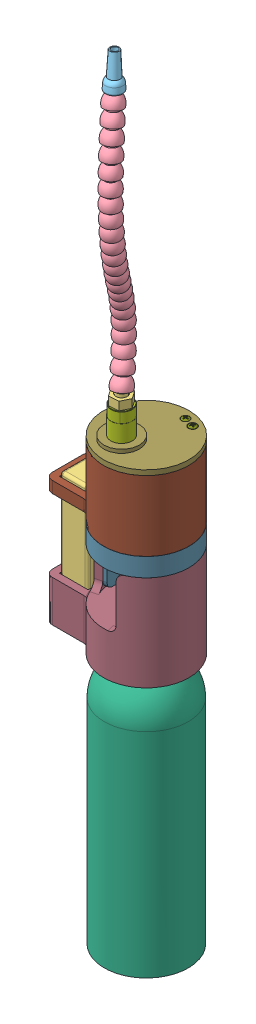
SolidWorks assembly _Robocup_Assembly_Wide_Straw_Thermos_, configuration Default. Lengths in mm.
Overall size (108.56 713.03 103.97).
85 component instances, 35 part files, 77 mates.
Components (placement in the parent):
- SF3218MG Servo-1: SF3218MG Servo [Default] at (-17.653 -62.7888 -19.9) size (54.86 45.72 19.05)
- Servo gear 30t-1: Servo gear 30t [Default] at (-7.993 -20.4688 -10.375) x (-0.381225 0 -0.924482) z (0 1 0) size (25.51 25.6 6)
- Coolant Pipe.stp-1: Coolant Pipe.stp [Default] at (-8.06 46.6882 14.01) x (0.568385 0 0.822762) z (-0.822762 0 0.568385) size (74.23 300.91 26.18)
  - Coolant Bolt.stp-1: Coolant Bolt.stp [Default] x (-1 0 0) z (0 0 1) size (17.61 27.5 15.25)
  - Connectors.stp-1: Connectors.stp [Default] at (-2.2835 3.6671 -0.0362) x (-0.321951 -0.100327 -0.941426) z (0.285439 -0.958386 0.00452) size (18.3 18.3 20)
  - Connectors.stp-2: Connectors.stp [Default] at (-0.9485 62.1668 -0.2193) x (0.834188 -0.338799 0.435138) z (-0.378337 -0.925657 0.00458) size (18.3 18.3 20)
  - Connectors.stp-3: Connectors.stp [Default] at (-7.0218 39.1054 -0.1142) x (0.974617 -0.052931 0.217534) z (-0.054998 -0.99848 0.003454) size (18.3 18.3 20)
  - Connectors.stp-4: Connectors.stp [Default] at (-7.018 27.1423 -0.0887) x (-0.288884 -0.031731 -0.956838) z (0.11095 -0.993826 -0.00054) size (18.3 18.3 20)
  - Connectors.stp-5: Connectors.stp [Default] at (10.0914 83.4503 -0.3173) x (0.525964 -0.304704 -0.794051) z (-0.497138 -0.867664 0.003658) size (18.3 18.3 20)
  - Connectors.stp-6: Connectors.stp [Default] at (4.2645 72.9625 -0.2712) x (0.886562 -0.462353 0.015441) z (-0.462461 -0.88663 0.004202) size (18.3 18.3 20)
  - Connectors.stp-7: Connectors.stp [Default] at (-4.9174 50.8742 -0.1644) x (0.803108 -0.192004 0.56405) z (-0.235547 -0.971852 0.004557) size (18.3 18.3 20)
  - Connectors.stp-8: Connectors.stp [Default] at (16.0513 93.8656 -0.3564) x (0.86534 -0.495122 -0.077724) z (-0.496415 -0.86808 0.003062) size (18.3 18.3 20)
  - Connectors.stp-9: Connectors.stp [Default] at (35.5838 137.5772 -0.4345) x (0.770438 -0.236558 0.592002) z (-0.293738 -0.955886 0.000312) size (18.3 18.3 20)
  - Connectors.stp-10: Connectors.stp [Default] at (38.4122 149.228 -0.4322) x (0.672162 -0.141658 -0.726727) z (-0.20668 -0.978409 -0.000445) size (18.3 18.3 20)
  - Connectors.stp-11: Connectors.stp [Default] at (31.7619 126.2108 -0.4277) x (0.912958 -0.361121 0.189996) z (-0.368012 -0.929821 0.001063) size (18.3 18.3 20)
  - Connectors.stp-12: Connectors.stp [Default] at (21.8052 104.3949 -0.3882) x (-0.461711 0.244191 -0.852756) z (-0.471034 -0.882112 0.002437) size (18.3 18.3 20)
  - Connectors.stp-13: Connectors.stp [Default] at (-5.2287 15.2947 -0.0801) x (0.757626 0.173214 -0.629285) z (0.225426 -0.974255 0.003232) size (18.3 18.3 20)
  - Connectors.stp-14: Connectors.stp [Default] at (27.1083 115.1559 -0.4121) x (0.901968 -0.4265 -0.067469) z (-0.427365 -0.904078 0.001774) size (18.3 18.3 20)
  - Coolant Pipe Nozzle.stp-1: Coolant Pipe Nozzle.stp [Default] at (27.898 246.6708 -0.2231) x (-0.153795 -0.02183 0.987862) z (0.098368 -0.995128 -0.006677) size (15 15 30)
  - Connectors.stp-15: Connectors.stp [Default] at (40.4307 185.0487 -0.3789) x (0.938856 0.053217 -0.340172) z (0.055817 -0.998439 -0.002147) size (18.3 18.3 20)
  - Connectors.stp-16: Connectors.stp [Default] at (39.2092 196.9799 -0.3507) x (0.937442 0.118696 -0.327281) z (0.124773 -0.992182 -0.002445) size (18.3 18.3 20)
  - Connectors.stp-17: Connectors.stp [Default] at (40.784 173.0623 -0.4029) x (0.972219 -0.02226 -0.233011) z (-0.023301 -0.999727 -0.001718) size (18.3 18.3 20)
  - Connectors.stp-18: Connectors.stp [Default] at (40.1447 161.0902 -0.4212) x (0.882181 -0.100002 -0.460169) z (-0.113225 -0.993569 -0.001143) size (18.3 18.3 20)
  - Connectors.stp-19: Connectors.stp [Default] at (31.9646 232.2183 -0.2574) x (0.793284 0.199128 0.575369) z (0.245233 -0.969461 -0.002594) size (18.3 18.3 20)
  - Connectors.stp-20: Connectors.stp [Default] at (37.2637 208.8167 -0.3201) x (0.26581 0.051415 -0.962653) z (0.180811 -0.983514 -0.002604) size (18.3 18.3 20)
  - Connectors.stp-21: Connectors.stp [Default] at (28.861 243.8093 -0.2266) x (0.725081 0.197806 0.659645) z (0.26534 -0.964151 -0.002545) size (18.3 18.3 20)
  - Connectors.stp-22: Connectors.stp [Default] at (34.7978 220.5587 -0.2886) x (0.975424 0.217793 -0.033387) z (0.217828 -0.975984 -0.002632) size (18.3 18.3 20)
- Thermos-1: Thermos [Default] at (0 -388.9327 0) x (0.026685 0 0.999644) z (-0.999644 0 0.026685) size (74.93 250.19 74.93)
- Arduino Nano.STEP-1: Arduino Nano.STEP [Default] at (17.196 -13.0397 29.7784) x (0 -1 0) z (1 0 0) size (44.28 18 13.68)
  - ATMEGA328P-AU.STEP.STEP-1: ATMEGA328P-AU.STEP.STEP [Default] at (19.8219 24.4243 4.0882) x (-0.707107 -0.707107 0) z (0 0 1) size (9 9 1.2)
    - ATMEGA328P-AU--3DModel-STEP-56544.step.STEP.STEP.STEP.STEP-1: ATMEGA328P-AU--3DModel-STEP-56544.step.STEP.STEP.STEP.STEP [Default] at (2.8163 4.1 0.6768) x (1 0 0) z (0 -1 0) size (9 1.2 9)
  - Arduino Nano.STEP-1: Arduino Nano.STEP [Default] at (8.8551 11.9484 0) size (43.18 18 6.8)
  - Mini USB.STEP-1: Mini USB.STEP [Default] at (8.5451 19.5727 4.14) size (9.5 9.7 3.9)
  - CSTCE Crystal.STEP-1: CSTCE Crystal.STEP [Default] at (25.8562 23.1047 4.15) x (0.707107 -0.707107 0) z (0 0 1) size (3.2 1.35 0.71)
  - 2Pin Tactile Switch 6x3.6.STEP-1: 2Pin Tactile Switch 6x3.6.STEP [Default] at (30.7142 19.8184 4.14) x (0 1 0) z (0 0 1) size (7.9 3.6 2.2)
  - 0603 Resistor.STEP-1: 0603 Resistor.STEP [Default] at (34.4251 22.4184 4.14) size (1.6 0.8 0.5)
  - 0603 Resistor.STEP-2: 0603 Resistor.STEP [Default] at (34.4251 20.7184 4.14) size (1.6 0.8 0.5)
  - 0603 Resistor.STEP-3: 0603 Resistor.STEP [Default] at (34.4251 18.9184 4.14) size (1.6 0.8 0.5)
  - 0603 Resistor.STEP-4: 0603 Resistor.STEP [Default] at (34.4251 17.2184 4.14) size (1.6 0.8 0.5)
  - Blue LED.STEP-1: Blue LED.STEP [Default] at (37.0251 22.4184 4.14) size (1.6 0.8 0.6)
  - Green LED.STEP-1: Green LED.STEP [Default] at (37.0251 20.7184 4.14) size (1.6 0.8 0.6)
  - Red LED.STEP-1: Red LED.STEP [Default] at (37.0251 18.9184 4.14) size (1.6 0.8 0.6)
  - Blue LED.STEP-2: Blue LED.STEP [Default] at (37.0251 17.2184 4.14) size (1.6 0.8 0.6)
  - Header 2x3.STEP-1: Header 2x3.STEP [Default] at (45.6765 17.0321 4.14) x (0 1 0) z (0 0 1) size (7.62 5.07 10)
  - SOT89.STEP-1: SOT89.STEP [Default] at (38.4751 17.3184 0.94) x (0 1 0) z (0 0 1) size (6.5 7.1 1.6)
  - 1206 Tantalum.STEP-1: 1206 Tantalum.STEP [Default] at (38.6251 22.3684 2.54) x (-1 0 0) z (0 0 -1) size (3.2 1.6 1.5)
  - 0603 Resistor.STEP-5: 0603 Resistor.STEP [Default] at (38.4251 24.9684 2.54) x (-1 0 0) z (0 0 -1) size (1.6 0.8 0.5)
  - 0603 Capacitor.STEP-1: 0603 Capacitor.STEP [Default] at (35.0338 14.4684 2.54) x (-1 0 0) z (0 0 -1) size (1.6 0.8 0.7)
  - 1206 Tantalum.STEP-2: 1206 Tantalum.STEP [Default] at (7.6451 24.3684 2.54) x (1 0 0) z (0 0 -1) size (3.2 1.6 1.5)
  - 0603 Capacitor.STEP-2: 0603 Capacitor.STEP [Default] at (6.9059 22.4745 2.54) x (-1 0 0) z (0 0 -1) size (1.6 0.8 0.7)
  - 0603 Capacitor.STEP-3: 0603 Capacitor.STEP [Default] at (17.8451 14.0245 2.54) x (-1 0 0) z (0 0 -1) size (1.6 0.8 0.7)
  - 0603 Capacitor.STEP-4: 0603 Capacitor.STEP [Default] at (17.8451 15.0767 2.54) x (-1 0 0) z (0 0 -1) size (1.6 0.8 0.7)
  - 0603 Capacitor.STEP-5: 0603 Capacitor.STEP [Default] at (25.3451 21.2855 2.54) x (-1 0 0) z (0 0 -1) size (1.6 0.8 0.7)
  - 0603 Resistor.STEP-6: 0603 Resistor.STEP [Default] at (23.8451 15.8601 2.54) x (-1 0 0) z (0 0 -1) size (1.6 0.8 0.5)
  - 0603 Resistor.STEP-7: 0603 Resistor.STEP [Default] at (23.8451 14.4709 2.54) x (-1 0 0) z (0 0 -1) size (1.6 0.8 0.5)
  - CSTCE Crystal.STEP-2: CSTCE Crystal.STEP [Default] at (13.1731 14.7184 2.53) x (-1 0 0) z (0 0 -1) size (3.2 1.35 0.71)
  - SOIC16.STEP-1: SOIC16.STEP [Default] at (16.6451 19.5642 2.54) x (-1 0 0) z (0 0 -1) size (10.2 6 1.5)
- 5V Battery-1: 5V Battery [Default] at (-51.308 -151.4427 0) x (-1 0 0) z (0 0 -1) size (24.89 102.87 26.92)
- 5111K751_Push-to-Connect Tube Fitting for Air and Water-1: 5111K751_Push-to-Connect Tube Fitting for Air and Water [5111K751] at (-3.81 -156.8527 6.5991) x (-0.837169 0 -0.546944) z (-0.546944 0 0.837169) size (20.16 24.38 17.46)
- 5111K751_Push-to-Connect Tube Fitting for Air and Water-2: 5111K751_Push-to-Connect Tube Fitting for Air and Water [5111K751] at (-3.81 -107.9327 6.5991) size (20.16 24.38 17.46)
- Robocup_Shaft-1: Robocup_Shaft [Default] at (-8.06 -77.47 14.01) x (0.635001 0 0.772511) z (-0.772511 0 0.635001) size (20.32 97.79 20.32)
- Robocup_Bushing-3: Robocup_Bushing [6383K234] at (-8.06 -67.3013 14.01) x (-0.988739 0 0.149647) z (0 -1 0) size (31.75 31.75 11.13)
- Robocup_Straw_Adapter-1: Robocup_Straw_Adapter [Default] at (-8.06 17.8372 14.01) x (0 1 0) z (-0.635001 0 -0.772511) size (24.57 19.05 19.05)
- Robocup_Spacer-1: Robocup_Spacer [Default] at (-8.06 -60.9386 14.01) x (0.976941 0 0.21351) z (-0.21351 0 0.976941) size (19.05 40.47 19.05)
- Robocup_Shaft_Collar-1: Robocup_Shaft_Collar [top] at (-8.06 -1.7988 14.01) x (0.448618 0 0.893723) z (0.893723 0 -0.448618) size (19.05 12.32 19.05)
- Robocup_Motor_Mount-1: Robocup_Motor_Mount [Default] at (2.54 -40.9448 -9.95) x (0 0 -1) z (1 0 0) size (71.12 62.53 65.19)
- Robocup_Motor_Shield-1: Robocup_Motor_Shield [Default] at (0 -62.5348 0) size (108.2 62.78 76.2)
- Robocup_Motor_Top-2: Robocup_Motor_Top [Default] at origin size (76.2 7.62 76.2)
- Robocup_Lid_Wide_Straw_Thermos-1: Robocup_Lid_Wide_Straw_Thermos [Default] at (0 -165.4127 0) size (108.2 85.45 76.2)
- Robocup_Motor_Base_Wide_Straw-2: Robocup_Motor_Base_Wide_Straw [Default] at (0 -106.9848 0) size (76.2 63.87 76.2)
- Robocup_Gear-2: Robocup_Gear [Default] at (-8.06 -20.4678 14.01) x (-0.387559 0 -0.921845) z (0 1 0) size (25.51 25.6 6.35)
- 91802A146_Passivated 18-8 Stainless Steel Phillips Oval Head Screws-1: 91802A146_Passivated 18-8 Stainless Steel Phillips Oval Head Screws [91802A146] at (-21.59 -35.7677 -15.201) x (0 -1 0) z (-0.546944 0 0.837169) size (10.75 6.65 6.65)
- 91802A146_Passivated 18-8 Stainless Steel Phillips Oval Head Screws-2: 91802A146_Passivated 18-8 Stainless Steel Phillips Oval Head Screws [91802A146] at (13.65 -0.3175 -27.73) x (0 -1 0) z (-0.520208 0 0.85404) size (10.75 6.65 6.65)
- 91802A146_Passivated 18-8 Stainless Steel Phillips Oval Head Screws-3: 91802A146_Passivated 18-8 Stainless Steel Phillips Oval Head Screws [91802A146] at (26.67 -35.7677 -5.549) x (0 -1 0) z (-0.546944 0 0.837169) size (10.75 6.65 6.65)
- 91802A146_Passivated 18-8 Stainless Steel Phillips Oval Head Screws-4: 91802A146_Passivated 18-8 Stainless Steel Phillips Oval Head Screws [91802A146] at (22.6869 -16.0655 3.182) x (1 0 0) z (0 -0.752403 0.658703) size (10.75 6.65 6.65)
- 91802A146_Passivated 18-8 Stainless Steel Phillips Oval Head Screws-5: 91802A146_Passivated 18-8 Stainless Steel Phillips Oval Head Screws [91802A146] at (26.67 -35.7677 -15.201) x (0 -1 0) z (0 0 1) size (10.75 6.65 6.65)
- 91802A146_Passivated 18-8 Stainless Steel Phillips Oval Head Screws-6: 91802A146_Passivated 18-8 Stainless Steel Phillips Oval Head Screws [91802A146] at (4.445 -63.4873 -30.48) x (0 -1 0) z (0 0 1) size (10.75 6.65 6.65)
- 91802A146_Passivated 18-8 Stainless Steel Phillips Oval Head Screws-7: 91802A146_Passivated 18-8 Stainless Steel Phillips Oval Head Screws [91802A146] at (-4.445 -63.4873 -30.48) x (0 -1 0) z (-0.546944 0 0.837169) size (10.75 6.65 6.65)
- 91802A146_Passivated 18-8 Stainless Steel Phillips Oval Head Screws-8: 91802A146_Passivated 18-8 Stainless Steel Phillips Oval Head Screws [91802A146] at (-21.59 -35.7677 -5.549) x (0 -1 0) z (0 0 1) size (10.75 6.65 6.65)
- 91802A146_Passivated 18-8 Stainless Steel Phillips Oval Head Screws-9: 91802A146_Passivated 18-8 Stainless Steel Phillips Oval Head Screws [91802A146] at (4.76 -0.3175 -30.27) x (0 -1 0) z (-0.999956 0 -0.009425) size (10.75 6.65 6.65)
- 91802A146_Passivated 18-8 Stainless Steel Phillips Oval Head Screws-11: 91802A146_Passivated 18-8 Stainless Steel Phillips Oval Head Screws [91802A146] at (-13.7901 -6.2438 16.8863) x (0.893723 0 -0.448618) z (-0.414893 -0.380394 -0.826538) size (10.75 6.65 6.65)
- 90480A007_Low-Strength Steel Hex Nut-1: 90480A007_Low-Strength Steel Hex Nut [90480A007] at (13.65 -3.9291 -27.73) x (0.931587 0 0.363518) z (-0.363518 0 0.931587) size (7.94 3.39 9.17)
- 90480A007_Low-Strength Steel Hex Nut-2: 90480A007_Low-Strength Steel Hex Nut [90480A007] at (4.76 -3.9291 -30.27) x (0.772389 0 -0.635149) z (0.635149 0 0.772389) size (7.94 3.39 9.17)
- 90480A007_Low-Strength Steel Hex Nut-3: 90480A007_Low-Strength Steel Hex Nut [90480A007] at (4.445 -67.0989 -30.48) size (7.94 3.39 9.17)
- 90480A007_Low-Strength Steel Hex Nut-4: 90480A007_Low-Strength Steel Hex Nut [90480A007] at (-4.445 -67.0989 -30.48) size (7.94 3.39 9.17)
Mates (geometry in assembly coordinates):
- Concentric6: concentric aligned: cylinder of robocup hollow shaft midfi-1 through (-8.06 20.32 14.01) axis (0 -1 0) radius 6.096; cylinder of Robocup bushing-3 through (-8.06 -72.0638 14.01) axis (0 -1 0) radius 6.35
- Concentric7: concentric anti-aligned: cylinder of robocup hollow shaft midfi-1 through (-8.06 20.32 14.01) axis (0 -1 0) radius 6.096; cylinder of shaft to fourth npt female midfi-1 through (-8.06 7.62 14.01) axis (0 1 0) radius 6.223
- Coincident13: coincident anti-aligned: plane of robocup hollow shaft midfi-1 through (-14.0482 20.32 17.2883) normal (0.635001 0 0.772511); plane of shaft to fourth npt female midfi-1 through (-12.7908 7.62 16.2547) normal (-0.635001 0 -0.772511)
- Coincident15: coincident anti-aligned: plane of robocup hollow shaft midfi-1 through (-8.06 20.32 14.01) normal (0 1 0); plane of shaft to fourth npt female midfi-1 through (-8.06 20.32 14.01) normal (0 -1 0)
- Concentric10: concentric aligned: cylinder of robocup hollow shaft midfi-1 through (-8.06 20.32 14.01) axis (0 -1 0) radius 6.096; cylinder of Robocup_Spacer-1 through (-8.06 -20.4678 14.01) axis (0 -1 0) radius 9.525
- Concentric12: concentric anti-aligned: cylinder of robocup hollow shaft midfi-1 through (-8.06 20.32 14.01) axis (0 -1 0) radius 6.096; cylinder of Robocup_Shaft_Collar-1 through (-8.06 -6.2438 14.01) axis (0 1 0) radius 9.525
- Concentric55: concentric aligned: circle of shaft to fourth npt female-1; circle of Coolant Pipe.stp-1/Coolant Bolt.stp-1
- Coincident109: coincident anti-aligned: plane of shaft to fourth npt female midfi-1 through (-8.06 32.1882 14.01) normal (0 1 0); plane of Coolant Pipe.stp-1/Coolant Bolt.stp-1 through (-8.06 32.1882 14.01) normal (0 -1 0)
- Coincident115: coincident anti-aligned: plane of Robocup Top Plate lowfi-2 through (0 0 0) normal (0 -1 0); plane of Robocup_Motor_Mount-1 through (0 0 0) normal (0 1 0)
- Coincident117: coincident anti-aligned: plane of Robocup_Motor_Shield-1 through (0 0 0) normal (0 1 0); plane of Robocup Top Plate lowfi-2 through (0 0 0) normal (0 -1 0)
- Coincident127: coincident anti-aligned: plane of Robocup bushing-3 through (-9.2963 -60.9386 5.8417) normal (0 1 0); plane of Robocup_Spacer-1 through (-8.06 -60.9386 14.01) normal (0 -1 0)
- Coincident131: coincident anti-aligned: plane of Robocup_Motor_Mount-1 through (21.336 22.5049 2.21) normal (-1 0 0); plane of Arduino Nano.STEP-1/Arduino Nano.STEP-1 through (21.336 -21.8948 17.83) normal (1 0 0)
- Coincident133: coincident anti-aligned: plane of Robocup_Motor_Mount-1 through (21.336 22.5049 1.21) normal (0 0 1); plane of Arduino Nano.STEP-1/Arduino Nano.STEP-1 through (21.336 -18.0848 1.21) normal (0 0 -1)
- Parallel1: parallel anti-aligned: plane of Robocup_Motor_Shield-1 through (0 -62.5348 0) normal (1 0 0); plane of Robocup_Motor_Mount-1 through (-29.4704 -62.5348 0) normal (-1 0 0)
- Coincident136: coincident aligned: plane of Robocup Top Plate lowfi-2 through (0 0 0) normal (0 0 1)
- Coincident137: coincident aligned: plane of Robocup Top Plate lowfi-2 through (0 0 0) normal (1 0 0)
- Coincident138: coincident aligned: plane of Robocup Top Plate lowfi-2 through (0 0 0) normal (0 1 0)
- Concentric77: concentric anti-aligned: cylinder of Robocup_Motor_Mount-1 through (0 -62.5348 0) axis (0 1 0) radius 35.56; cylinder of Robocup_Motor_Shield-1 through (0 0 0) axis (0 -1 0) radius 38.1
- Parallel6: parallel aligned: plane of Robocup_Motor_Mount-1 through (2.54 -40.9448 -9.95) normal (1 0 0)
- Concentric78: concentric aligned: cylinder of SF3218MG Servo-1 through (-7.993 39.4275 -10.375) axis (0 -1 0) radius 3.81; cylinder of Servo gear 30t-1 through (-7.993 11.0983 -10.375) axis (0 -1 0) radius 3.85
- Coincident165: coincident anti-aligned: plane of SF3218MG Servo-1 through (-17.653 -62.7888 -19.9) normal (0 0 -1); plane of Robocup_Motor_Mount-1 through (-17.78 -35.8648 -19.9) normal (0 0 1)
- Coincident166: coincident anti-aligned: plane of SF3218MG Servo-1 through (-17.653 -35.8648 -27.7545) normal (0 -1 0); plane of Robocup_Motor_Mount-1 through (2.54 -35.8648 -9.95) normal (0 1 0)
- Coincident168: coincident anti-aligned: plane of SF3218MG Servo-1 through (-17.653 -17.0688 -0.85) normal (0 1 0); plane of Servo gear 30t-1 through (-7.993 -17.0688 -10.375) normal (0 -1 0)
- Concentric79: concentric anti-aligned: cylinder of Robocup_Lid_Wide_Straw_Thermos-1 through (0 -165.4127 0) axis (0 -1 0) radius 38.1; cylinder of Robocup_Motor_Base_Wide_Straw-2 through (0 -186.8158 0) axis (0 1 0) radius 38.1
- Coincident170: coincident aligned: plane of Robocup_Lid_Wide_Straw_Thermos-1 through (0 -165.4127 0) normal (1 0 0); plane of Robocup_Motor_Base_Wide_Straw-2 through (0 -106.9848 0) normal (1 0 0)
- Coincident171: coincident aligned: plane of Robocup_Lid_Wide_Straw_Thermos-1 through (0 -165.4127 0) normal (1 0 0)
- Coincident172: coincident aligned: plane of Robocup_Lid_Wide_Straw_Thermos-1 through (0 -165.4127 0) normal (0 0 1)
- Concentric84: concentric anti-aligned: cylinder of Robocup_Motor_Mount-1 through (0 -62.5348 0) axis (0 1 0) radius 35.56; cylinder of Robocup_Lid_Wide_Straw_Thermos-1 through (0 -165.4127 0) axis (0 -1 0) radius 38.1
- Concentric85: concentric aligned: cylinder of Thermos-1 through (0 -388.9327 0) axis (0 -1 0) radius 24.384; cylinder of Robocup_Lid_Wide_Straw_Thermos-1 through (0 -165.4127 0) axis (0 -1 0) radius 38.1
- Coincident175: coincident anti-aligned: plane of Robocup bushing-3 through (-9.664 -64.0628 3.4119) normal (0 -1 0); plane of Robocup_Motor_Base_Wide_Straw-2 through (-1.0936 -64.0628 1.9012) normal (0 1 0)
- Coincident178: coincident anti-aligned: plane of 5V Battery-1 through (-51.308 -151.4427 0) normal (0 0 -1)
- Coincident180: coincident anti-aligned: plane of 5V Battery-1 through (-63.754 -48.5727 13.462) normal (-1 0 0); plane of Robocup_Lid_Wide_Straw_Thermos-1 through (-63.754 -71.9998 13.843) normal (1 0 0)
- Coincident181: coincident anti-aligned: plane of Robocup_Lid_Wide_Straw_Thermos-1 through (0 -126.0427 0) normal (0 1 0); plane of Robocup_Motor_Base_Wide_Straw-2 through (0 -126.0427 0) normal (0 -1 0)
- Coincident187: coincident anti-aligned: plane of Robocup_Motor_Mount-1 through (2.54 -61.2648 -9.95) normal (0 1 0); plane of Arduino Nano.STEP-1/Arduino Nano.STEP-1 through (21.336 -61.2648 1.21) normal (0 -1 0)
- Concentric90: concentric aligned: cylinder of robocup hollow shaft midfi-1 through (-8.06 20.32 14.01) axis (0 -1 0) radius 6.096; cylinder of robocup straw gear 30t-2 through (-8.06 -14.4678 14.01) axis (0 -1 0) radius 6.223
- Coincident188: coincident anti-aligned: plane of Robocup_Spacer-1 through (-8.06 -20.4678 14.01) normal (0 1 0); plane of robocup straw gear 30t-2 through (-19.297 -20.4678 19.2561) normal (0 -1 0)
- Coincident190: coincident anti-aligned: plane of Robocup_Motor_Mount-1 through (2.54 -62.5348 -9.95) normal (0 -1 0); plane of Robocup_Motor_Base_Wide_Straw-2 through (0 -62.5348 0) normal (0 1 0)
- Coincident191: coincident anti-aligned: plane of Robocup_Shaft_Collar-1 through (-8.06 -14.1178 14.01) normal (0 -1 0); plane of robocup straw gear 30t-2 through (-2.7381 -14.1178 24.9065) normal (0 1 0)
- Distance1: distance = 0.635 mm anti-aligned: plane of SF3218MG Servo-1 through (22.733 -62.7888 -0.85) normal (1 0 0); plane of robocup servo mount mid-fi-1 through (23.368 -62.5348 0) normal (-1 0 0)
- Concentric92: concentric aligned: cylinder of Robocup Top Plate lowfi-2 through (13.65 0 -27.73) axis (0 1 0) radius 1.778; circle of 91802A146_Passivated 18-8 Stainless Steel Phillips Oval Head Screws-2
- Coincident193: coincident aligned: plane of Robocup Top Plate lowfi-2 through (0 4.445 0) normal (0 1 0); circle of 91802A146_Passivated 18-8 Stainless Steel Phillips Oval Head Screws-2
- Concentric94: concentric aligned: circle of 91802A146_Passivated 18-8 Stainless Steel Phillips Oval Head Screws-9; circle of Robocup Top Plate midfi-2
- Coincident194: coincident aligned: plane of Robocup Top Plate lowfi-2 through (0 4.445 0) normal (0 1 0); circle of 91802A146_Passivated 18-8 Stainless Steel Phillips Oval Head Screws-9
- Concentric95: concentric anti-aligned: cylinder of Robocup_Motor_Mount-1 through (4.445 -37.1348 -30.48) axis (0 -1 0) radius 2.032; circle of 91802A146_Passivated 18-8 Stainless Steel Phillips Oval Head Screws-6
- Coincident195: coincident aligned: plane of Robocup_Motor_Mount-1 through (2.54 -58.7248 -9.95) normal (0 1 0); circle of 91802A146_Passivated 18-8 Stainless Steel Phillips Oval Head Screws-6
- Concentric96: concentric anti-aligned: cylinder of Robocup_Motor_Mount-1 through (-4.445 -37.1348 -30.48) axis (0 -1 0) radius 2.032; circle of 91802A146_Passivated 18-8 Stainless Steel Phillips Oval Head Screws-7
- Coincident196: coincident aligned: plane of Robocup_Motor_Mount-1 through (2.54 -58.7248 -9.95) normal (0 1 0); circle of 91802A146_Passivated 18-8 Stainless Steel Phillips Oval Head Screws-7
- Concentric97: concentric aligned: cylinder of SF3218MG Servo-1 through (-21.59 -62.7888 -15.201) axis (0 1 0) radius 2.54; circle of 91802A146_Passivated 18-8 Stainless Steel Phillips Oval Head Screws-1
- Coincident197: coincident aligned: plane of SF3218MG Servo-1 through (-17.653 -32.8168 -27.7545) normal (0 1 0); circle of 91802A146_Passivated 18-8 Stainless Steel Phillips Oval Head Screws-1
- Coincident198: coincident aligned: plane of SF3218MG Servo-1 through (-17.653 -32.8168 -27.7545) normal (0 1 0); circle of 91802A146_Passivated 18-8 Stainless Steel Phillips Oval Head Screws-8
- Concentric98: concentric aligned: cylinder of SF3218MG Servo-1 through (-21.59 -62.7888 -5.549) axis (0 1 0) radius 2.54; circle of 91802A146_Passivated 18-8 Stainless Steel Phillips Oval Head Screws-8
- Coincident199: coincident aligned: plane of SF3218MG Servo-1 through (22.733 -32.8168 -27.7545) normal (0 1 0); circle of 91802A146_Passivated 18-8 Stainless Steel Phillips Oval Head Screws-5
- Concentric99: concentric aligned: cylinder of SF3218MG Servo-1 through (26.67 -62.7888 -15.201) axis (0 1 0) radius 2.54; circle of 91802A146_Passivated 18-8 Stainless Steel Phillips Oval Head Screws-5
- Concentric100: concentric aligned: circle of SF3218MG Servo-1; circle of 91802A146_Passivated 18-8 Stainless Steel Phillips Oval Head Screws-3
- Coincident200: coincident aligned: plane of SF3218MG Servo-1 through (22.733 -32.8168 -27.7545) normal (0 1 0); circle of 91802A146_Passivated 18-8 Stainless Steel Phillips Oval Head Screws-3
- Concentric101: concentric aligned: cylinder of Robocup_Motor_Mount-1 through (34.4929 -16.0655 3.182) axis (-1 0 0) radius 1.778; circle of 91802A146_Passivated 18-8 Stainless Steel Phillips Oval Head Screws-4
- Coincident201: coincident aligned: plane of Arduino Nano.STEP-1/Arduino Nano.STEP-1 through (19.736 -21.8948 17.83) normal (-1 0 0); circle of 91802A146_Passivated 18-8 Stainless Steel Phillips Oval Head Screws-4
- Concentric106: concentric anti-aligned: cylinder of Robocup_Shaft_Collar-1 through (-16.5727 -6.2438 18.2831) axis (0.893723 0 -0.448618) radius 1.7145; circle of 91802A146_Passivated 18-8 Stainless Steel Phillips Oval Head Screws-11
- Tangent9: tangent: cylinder of Robocup_Shaft_Collar-1 through (-8.06 -6.2438 14.01) axis (0 1 0) radius 9.525; circle of 91802A146_Passivated 18-8 Stainless Steel Phillips Oval Head Screws-11
- Concentric107: concentric aligned: cylinder of robocup hollow shaft midfi-1 through (-8.06 20.32 14.01) axis (0 -1 0) radius 6.096; cylinder of Robocup Top Plate lowfi-2 through (-8.06 7.62 14.01) axis (0 -1 0) radius 6.35
- Coincident202: coincident anti-aligned: plane of shaft to fourth npt female midfi-1 through (-8.06 7.62 14.01) normal (0 -1 0); plane of Robocup Top Plate lowfi-2 through (-8.06 7.62 14.01) normal (0 1 0)
- Coincident203: coincident anti-aligned: plane of Robocup_Motor_Mount-1 through (2.54 -2.54 -9.95) normal (0 -1 0); plane of 90480A007_Low-Strength Steel Hex Nut-1 through (10.7857 -2.54 -31.3073) normal (0 1 0)
- Coincident204: coincident anti-aligned: plane of Robocup_Motor_Mount-1 through (2.54 -2.54 -9.95) normal (0 -1 0); plane of 90480A007_Low-Strength Steel Hex Nut-2 through (0.2392 -2.54 -29.5191) normal (0 1 0)
- Concentric109: concentric anti-aligned: circle of Robocup Top Plate lowfi-2; circle of 90480A007_Low-Strength Steel Hex Nut-2
- Concentric110: concentric aligned: circle of 91802A146_Passivated 18-8 Stainless Steel Phillips Oval Head Screws-2; circle of 90480A007_Low-Strength Steel Hex Nut-1
- Parallel9: parallel anti-aligned: plane of Robocup_Motor_Mount-1 through (21.9136 -8.89 -35.8592) normal (-0.931587 0 -0.363518); plane of 90480A007_Low-Strength Steel Hex Nut-1 through (16.5143 -2.54 -24.1527) normal (0.931587 0 0.363518)
- Parallel10: parallel anti-aligned: plane of Robocup_Motor_Mount-1 through (1.82 -8.89 -34.2344) normal (0.93625 0 0.351334); plane of 90480A007_Low-Strength Steel Hex Nut-2 through (1.8493 -2.54 -33.8096) normal (-0.93625 0 -0.351334)
- Coincident205: coincident anti-aligned: plane of Robocup_Motor_Base_Wide_Straw-2 through (0 -65.7098 0) normal (0 -1 0); plane of 90480A007_Low-Strength Steel Hex Nut-4 through (-8.4137 -65.7098 -32.7714) normal (0 1 0)
- Coincident206: coincident anti-aligned: plane of Robocup_Motor_Base_Wide_Straw-2 through (0 -65.7098 0) normal (0 -1 0); plane of 90480A007_Low-Strength Steel Hex Nut-3 through (0.4763 -65.7098 -32.7714) normal (0 1 0)
- Concentric112: concentric anti-aligned: circle of motorbox bottom low-fi-1; circle of 90480A007_Low-Strength Steel Hex Nut-3
- Concentric113: concentric anti-aligned: circle of motorbox bottom low-fi-1; circle of 90480A007_Low-Strength Steel Hex Nut-4
- Coincident207: coincident anti-aligned: plane of 5V Battery-1 through (-51.308 -151.4427 0) normal (0 -1 0); plane of Robocup_Lid_Wide_Straw_Thermos-1 through (0 -151.4427 0) normal (0 1 0)
- Coincident208: coincident anti-aligned: plane of Thermos-1 through (0.6507 -138.7427 24.3753) normal (0 1 0); plane of Robocup_Lid_Wide_Straw_Thermos-1 through (0 -138.7427 0) normal (0 -1 0)
- Coincident209: coincident anti-aligned: plane of Robocup_Lid_Wide_Straw_Thermos-1 through (0 -126.0427 0) normal (0 1 0); plane of 5111K751_Push-to-Connect Tube Fitting for Air and Water-2 through (-3.81 -126.0427 6.5991) normal (0 -1 0)
- Concentric114: concentric aligned: cylinder of Robocup_Lid_Wide_Straw_Thermos-1 through (-3.81 -165.4127 6.5991) axis (0 1 0) radius 3.175; cylinder of 5111K751_Push-to-Connect Tube Fitting for Air and Water-2 through (-3.81 -137.0101 6.5991) axis (0 1 0) radius 4.765
- Coincident210: coincident anti-aligned: plane of Robocup_Lid_Wide_Straw_Thermos-1 through (0 -138.7427 0) normal (0 -1 0); plane of 5111K751_Push-to-Connect Tube Fitting for Air and Water-1 through (-3.81 -138.7427 6.5991) normal (0 1 0)
- Concentric115: concentric anti-aligned: cylinder of Robocup_Lid_Wide_Straw_Thermos-1 through (-3.81 -165.4127 6.5991) axis (0 1 0) radius 3.175; cylinder of 5111K751_Push-to-Connect Tube Fitting for Air and Water-1 through (-3.81 -127.7752 6.5991) axis (0 -1 0) radius 4.765
